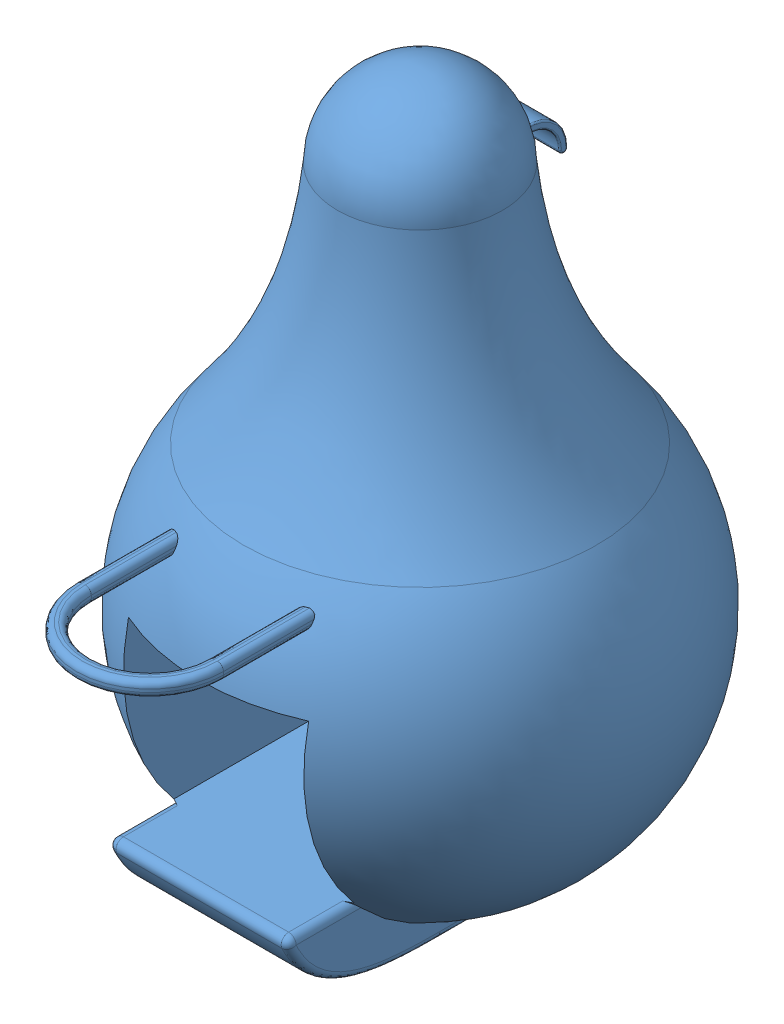
SolidWorks assembly assembly ruwe schets, configuration Default. Lengths in mm.
Overall size (300 454.81 378.93).
14 component instances, 12 part files, 3 mates.
Components (placement in the parent):
- ruwe Cad Nespresso-1: ruwe Cad Nespresso [Default] at (-29.9732 -227.8526 18.0642) size (300 454.81 378.93)
- dispenser-1: dispenser [Default] at (-28.3202 84.2666 45.8089) x (1 0 0) z (0 -0.819152 0.573576) size (91 62.05 176.36)
  - Schenk cilinder-1: Schenk cilinder [Default] at origin size (87.3 53 176.36)
  - Cup crusher-1: Cup crusher [Default] at (26 0 91.6093) x (-1 0 0) z (0 0 1) size (54.82 51.43 61)
  - Arm-1: Arm [right arm] at (9.5 17.3099 48.9599) x (-1 0 0) z (0 0.805266 0.592914) size (11 57.23 23.97)
  - Arm-2: Arm [Default] at (-9.5 17.3099 48.9599) x (-1 0 0) z (0 0.805266 0.592914) size (11 57.23 23.97)
  - Pusher-1: Pusher [Default] at (0 18.7662 51.3963) x (-1 0 0) z (0 -0.513057 -0.858355) size (46 35.9 49.33)
  - As-1: As [Default] at (45.4979 0 20) x (0 -0.98643 0.164182) z (-1 0 0) size (13 13 91)
- ECU-1: ECU [Default] at (91.1201 -101.6237 -30.7116) x (0.358368 0.93358 0) z (0 0 1) size (117 33 76)
- Hitte element-1: Hitte element [Default] at (3.1271 -43.8778 36.2549) x (0.995443 0.031848 -0.089887) z (-0.089583 -0.01084 -0.99592) size (131.13 62 104)
- onderdeel koffiezetapparaat-1: onderdeel koffiezetapparaat [Default] at (-90.6931 -26.7337 8.5841) size (35 49.5 29)
- Water entry-1: Water entry [Default] at (-93.2578 20.9471 6.1209) size (30.21 45 21.08)
- Pomp onderdeel-2: Pomp onderdeel [Default] at (-128.3241 -65.8116 16.5675) x (-0.993572 0 -0.113203) z (0.113203 0 -0.993572) size (54 123 56.5)
- cupjes afvalbakje-1: cupjes afvalbakje [Default] at (-29.9732 -177.8526 -36.9358) size (120 120 87)
Mates (geometry in assembly coordinates):
- Coincident2: coincident anti-aligned: plane of ruwe Cad Nespresso-1 through (30.0268 -177.8526 -1.9358) normal (-1 0 0); plane of cupjes afvalbakje-1 through (30.0268 -57.8526 -1.9358) normal (1 0 0)
- Coincident3: coincident anti-aligned: plane of ruwe Cad Nespresso-1 through (-89.9732 -57.8526 -1.9358) normal (0 -1 0); plane of cupjes afvalbakje-1 through (-29.9732 -57.8526 -36.9358) normal (0 1 0)
- Coincident4: coincident aligned: plane of ruwe Cad Nespresso-1 through (-29.9732 -227.8526 -1.9358) normal (0 0 1); plane of cupjes afvalbakje-1 through (-89.9732 -57.8526 -1.9358) normal (0 0 1)
